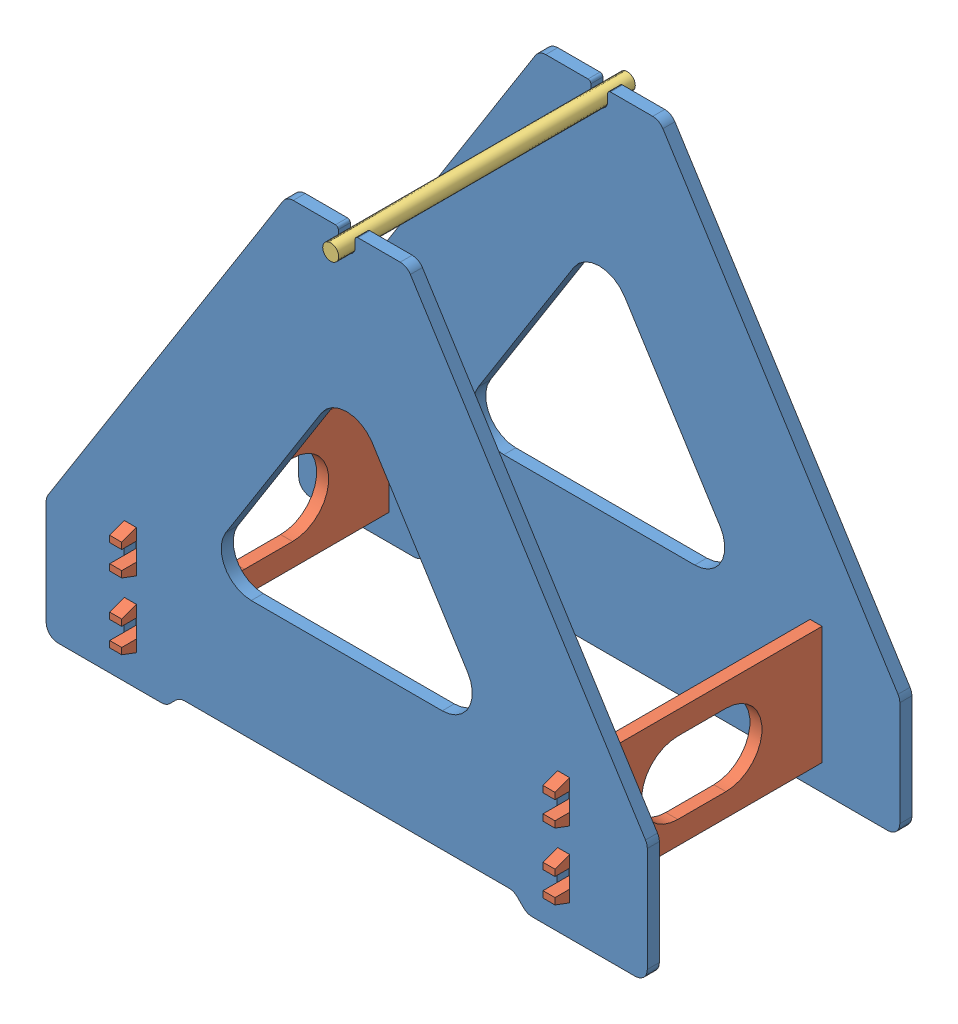
SolidWorks assembly spool_holder, configuration Default. Lengths in mm.
Overall size (300 250 148).
5 component instances, 3 part files, 14 mates.
Components (placement in the parent):
- spool_holder_side-1: spool_holder_side [Default] at origin size (300 250 6)
- spool_holder_crossbar-1: spool_holder_crossbar [Default] at (-105 0 0) x (0 0 1) z (-1 0 0) size (146.56 58.9 6)
- spool_holder_crossbar-2: spool_holder_crossbar [Default] at (105.2 0 -120) x (0 0 -1) z (1 0 0) size (146.56 58.9 6)
- spool_holder_side-2: spool_holder_side [Default] at (0 0 -126) size (300 250 6)
- spool_bar^spool_holder-1: spool_bar^spool_holder [Default] x (-1 0 0) z (0 0 -1) size (8 8 148) (virtual)
Mates (geometry in assembly coordinates):
- SulPosto1: in place: plane of spool_holder_side-1 through (-105 0 6) normal (-1 0 0); plane of spool_holder_crossbar-1 through (-105 0 0) normal (-1 0 0); moOrthogonalPlaneRef_w of spool_holder_side-1 through (-105 0 6) normal (-1 0 0); plane of spool_holder_crossbar-1 through (-105 0 0) normal (0 1 0); plane of spool_holder_side-1 through (-105 0 6) normal (-1 0 0); plane of spool_holder_crossbar-1 through (-105 0 0) normal (0 0 1); plane of spool_holder_side-1 through (-105 0 6) normal (-1 0 0); unknown of spool_holder_crossbar-1
- Coincidente1: coincident aligned: plane of spool_holder_side-1; plane of spool_holder_crossbar-1
- Coincidente2: coincident aligned: moOrthogonalPlaneRef_w of spool_holder_side-1 through (-105 0 0) normal (0 1 0); plane of spool_holder_crossbar-1 through (-105 0 0) normal (0 1 0)
- Coincidente3: coincident anti-aligned: moOrthogonalPlaneRef_w of spool_holder_side-1 through (-105 0 0) normal (0 0 -1); plane of spool_holder_crossbar-1 through (-105 0 0) normal (0 0 1)
- Coincidente4: coincident anti-aligned: plane of spool_holder_side-1 through (111.2 0 6) normal (-1 0 0); plane of spool_holder_crossbar-2 through (111.2 0 -120) normal (1 0 0)
- Coincidente5: coincident anti-aligned: plane of spool_holder_side-1 through (0 0 0) normal (0 0 -1); plane of spool_holder_crossbar-2 through (111.2 -100.594 0) normal (0 0 1)
- Coincidente6: coincident anti-aligned: plane of spool_holder_side-1 through (0 -133.794 6) normal (0 1 0); plane of spool_holder_crossbar-2 through (111.2 -133.794 6) normal (0 -1 0)
- Coincidente7: coincident anti-aligned: plane of spool_holder_crossbar-2 through (111.2 -100.594 -120) normal (0 0 -1); plane of spool_holder_side-2 through (0 0 -120) normal (0 0 1)
- Coincidente8: coincident anti-aligned: plane of spool_holder_crossbar-2 through (111.2 -133.794 -126) normal (0 -1 0); plane of spool_holder_side-2 through (0 -133.794 -120) normal (0 1 0)
- Coincidente9: coincident anti-aligned: plane of spool_holder_crossbar-2 through (111.2 0 -120) normal (1 0 0); plane of spool_holder_side-2 through (111.2 0 -120) normal (-1 0 0)
- SulPosto2: in place: plane of spool_holder_side-1 through (0 0 0) normal (0 0 -1); plane of spool_bar^spool_holder-1 through (0 0 0) normal (0 0 -1); plane of spool_holder_side-1 through (0 0 0) normal (0 0 -1); plane of spool_bar^spool_holder-1 through (0 0 0) normal (0 1 0); plane of spool_holder_side-1 through (0 0 0) normal (0 0 -1); plane of spool_bar^spool_holder-1 through (0 0 0) normal (-1 0 0); plane of spool_holder_side-1 through (0 0 0) normal (0 0 -1); unknown of spool_bar^spool_holder-1
- Coincidente10: coincident aligned: plane of spool_holder_side-1; plane of spool_bar^spool_holder-1
- Coincidente11: coincident aligned: moOrthogonalPlaneRef_w of spool_holder_side-1 through (0 0 0) normal (0 1 0); plane of spool_bar^spool_holder-1 through (0 0 0) normal (0 1 0)
- Coincidente12: coincident anti-aligned: moOrthogonalPlaneRef_w of spool_holder_side-1 through (0 0 0) normal (1 0 0); plane of spool_bar^spool_holder-1 through (0 0 0) normal (-1 0 0)
